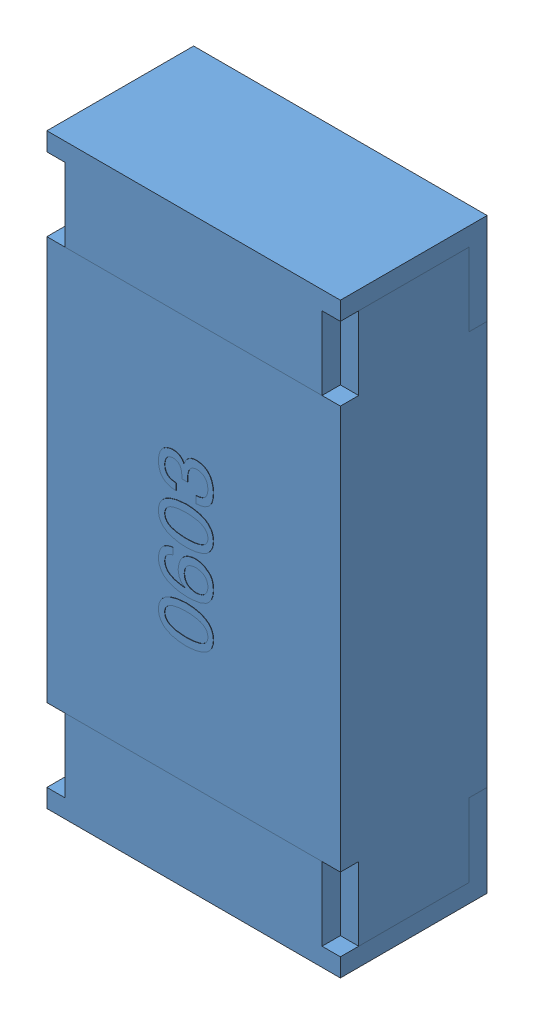
SolidWorks assembly 0603电阻, configuration 默认. Lengths in mm.
Overall size (0.8 1.6 0.4).
2 component instances, 1 part files, 0 mates.
Components (placement in the parent):
- R_0603^0603电阻-1: R_0603^0603电阻 [默认] at (138.684 113.411 0) x (0 1 0) z (0 0 1) size (1.6 0.8 0.4) (virtual)
  - R_0603-25^R_0603_0603电阻-1: R_0603-25^R_0603_0603电阻 [默认] at origin size (1.6 0.8 0.4) (virtual)
